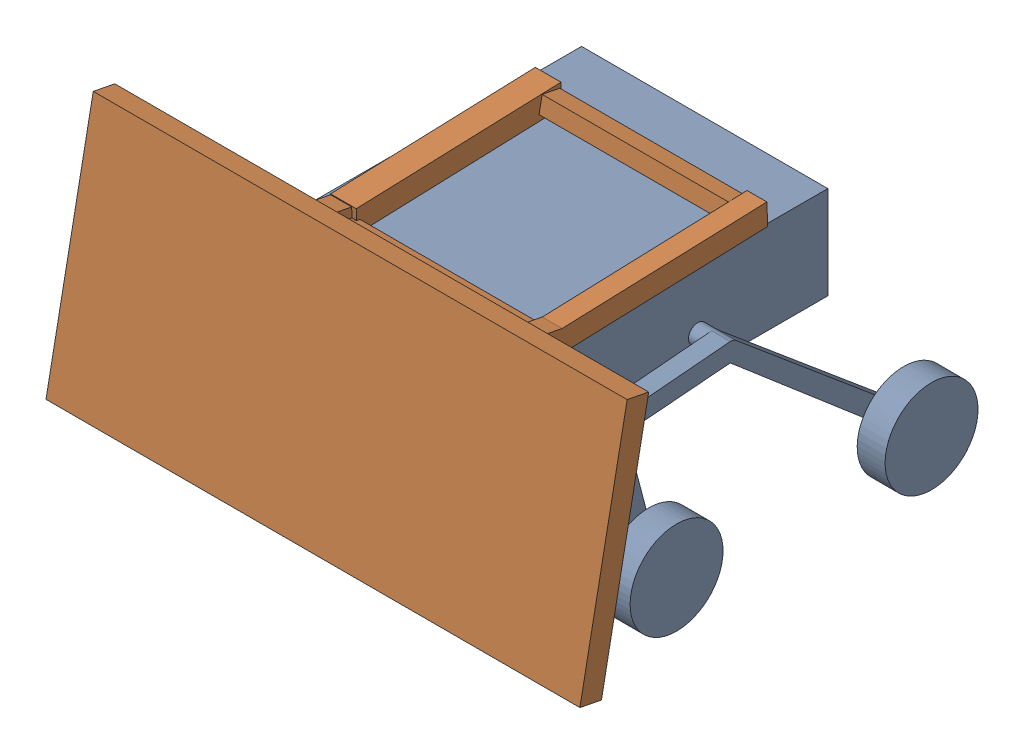
SolidWorks assembly Assem12, configuration Default. Lengths in mm.
Overall size (1459.3 920.49 1325.41).
2 component instances, 2 part files, 0 mates.
Components (placement in the parent):
- Rover-1: Rover [Default] at (-377.3757 129.1895 499.196) size (1003.3 689.78 1007.34)
- Part39-1: Part39 [Default] at (-29.7083 251.2103 668.2792) x (1 0 0) z (0 0.981627 -0.190809) size (1459.3 768.66 731.53)
